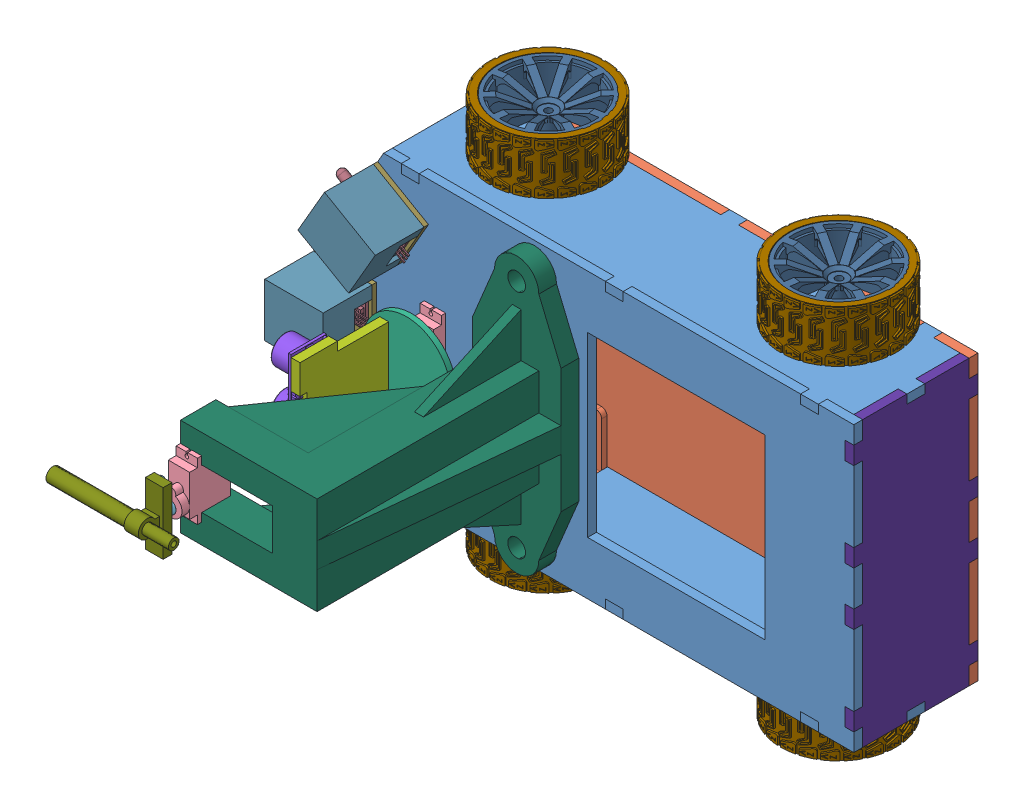
SolidWorks assembly Assemblage1, configuration Défaut. Lengths in mm.
Overall size (311.28 221.6 246.41).
49 component instances, 20 part files, 76 mates.
Components (placement in the parent):
- sides cage-1: sides cage [Défaut] at (1.2167 74.5307 344.188) x (1 0 0) z (0 -1 0) size (265 70 5)
- Support moteur-1: Support moteur [Défaut] at (-83.1833 74.5307 314.388) x (0 -1 0) z (-1 0 0) size (33 33 26)
- Support moteur-2: Support moteur [Défaut] at (80.6167 74.5307 314.388) x (0 -1 0) z (-1 0 0) size (33 33 26)
- GearMotor_25GA370-34 24V-TRUNSUN-1: GearMotor_25GA370-34 24V-TRUNSUN [Predeterminada] at (-83.1833 71.5307 334.388) x (0 -1 0) z (1 0 0) size (68.96 25 25)
- GearMotor_25GA370-34 24V-TRUNSUN-2: GearMotor_25GA370-34 24V-TRUNSUN [Predeterminada] at (80.6167 71.5307 334.388) x (0 -1 0) z (1 0 0) size (68.96 25 25)
- sides cage-4: sides cage [Défaut] at (1.2167 -80.4693 344.188) x (1 0 0) z (0 -1 0) size (265 70 5)
- Support moteur-3: Support moteur [Défaut] at (-83.1833 -85.4693 314.388) x (0 1 0) z (1 0 0) size (33 33 26)
- Support moteur-4: Support moteur [Défaut] at (80.6167 -85.4693 314.388) x (0 1 0) z (1 0 0) size (33 33 26)
- GearMotor_25GA370-34 24V-TRUNSUN-3: GearMotor_25GA370-34 24V-TRUNSUN [Predeterminada] at (-83.1833 -82.4693 334.388) x (0 1 0) z (-1 0 0) size (68.96 25 25)
- GearMotor_25GA370-34 24V-TRUNSUN-4: GearMotor_25GA370-34 24V-TRUNSUN [Predeterminada] at (80.6167 -82.4693 334.388) x (0 1 0) z (-1 0 0) size (68.96 25 25)
- rough_body-1: rough_body [Default] at (-102.2833 -2.1693 385.988) x (0 1 0) z (1 0 0) size (32.4 30.3 12)
- part 7 .1-1: part 7 .1 [Default] at (-102.2833 -7.6693 392.2972) x (1 0 0) z (0 1 0) size (7.3 5 34)
- base-1: base [Default] at (-102.2833 -7.6693 392.2972) x (0 1 0) z (0 0 1) size (50 50 3)
- vertical-1: vertical [Default] at (-117.2833 -7.6693 420.2972) x (0 1 0) z (1 0 0) size (45 53 5)
- compUltrasonic HCSR04-1: compUltrasonic HCSR04 [Default] at (-118.7833 41.4801 356.1344) x (0 1 0) z (-1 0 0) size (45 24.45 19.22)
- wheel-6: wheel [Default] at (90.8734 -44.1342 276.598) x (1 0 0) z (0 -1 0) size (65.01 65.01 29.8)
  - 65mm tire-1: 65mm tire [Default] at (-10.6774 57.7897 57.6351) size (65.01 65.01 29)
  - blue_wheel_frame-1: blue_wheel_frame [Default] at (-10.2563 57.7897 57.6351) x (0 0 -1) z (0.137869 0.990451 0) size (29 56 56)
  - motor_adapter-2: motor_adapter [Default] at (-10.2567 57.79 54.3351) x (0.788821 -0.614623 0) z (0 0 1) size (13.7 12 18.23)
- wheel-7: wheel [Default] at (-72.9266 -44.1342 276.598) x (1 0 0) z (0 -1 0) size (65.01 65.01 29.8)
  - 65mm tire-1: 65mm tire [Default] at (-10.6774 57.7897 57.6351) size (65.01 65.01 29)
  - blue_wheel_frame-1: blue_wheel_frame [Default] at (-10.2563 57.7897 57.6351) x (0 0 -1) z (0.137869 0.990451 0) size (29 56 56)
  - motor_adapter-2: motor_adapter [Default] at (-10.2567 57.79 54.3351) x (0.788821 -0.614623 0) z (0 0 1) size (13.7 12 18.23)
- wheel-8: wheel [Default] at (90.8734 33.1955 392.178) x (1 0 0) z (0 1 0) size (65.01 65.01 29.8)
  - 65mm tire-1: 65mm tire [Default] at (-10.6774 57.7897 57.6351) size (65.01 65.01 29)
  - blue_wheel_frame-1: blue_wheel_frame [Default] at (-10.2563 57.7897 57.6351) x (0 0 -1) z (0.137869 0.990451 0) size (29 56 56)
  - motor_adapter-2: motor_adapter [Default] at (-10.2567 57.79 54.3351) x (0.788821 -0.614623 0) z (0 0 1) size (13.7 12 18.23)
- wheel-9: wheel [Default] at (-72.9266 33.1955 392.178) x (1 0 0) z (0 1 0) size (65.01 65.01 29.8)
  - 65mm tire-1: 65mm tire [Default] at (-10.6774 57.7897 57.6351) size (65.01 65.01 29)
  - blue_wheel_frame-1: blue_wheel_frame [Default] at (-10.2563 57.7897 57.6351) x (0 0 -1) z (0.137869 0.990451 0) size (29 56 56)
  - motor_adapter-2: motor_adapter [Default] at (-10.2567 57.79 54.3351) x (0.788821 -0.614623 0) z (0 0 1) size (13.7 12 18.23)
- BASSE BC IR-1: BASSE BC IR [Défaut] at (-125.773 51.0749 379.188) x (0.866025 -0.5 0) z (0 0 1) size (33 30 2.5)
- Light sensor LM393-1: Light sensor LM393 [По умолчанию] at (-128.3725 48.0724 382.188) x (-0.866025 0.5 0) z (0.5 0.866025 0) size (46.18 7.1 14.2)
- cache bc IR-1: cache bc IR [Défaut] at (-129.773 44.1467 409.188) x (0.866025 -0.5 0) z (0 0 -1) size (33 30 30)
- BASSE BC IR-2: BASSE BC IR [Défaut] at (-129.773 -55.0854 379.188) x (0.866025 0.5 0) z (0 0 1) size (33 30 2.5)
- Light sensor LM393-2: Light sensor LM393 [По умолчанию] at (-128.4725 -58.8379 382.188) x (-0.866025 -0.5 0) z (-0.5 0.866025 0) size (46.18 7.1 14.2)
- cache bc IR-2: cache bc IR [Défaut] at (-125.773 -62.0136 409.188) x (0.866025 0.5 0) z (0 0 -1) size (33 30 30)
- BASSE BC IR-3: BASSE BC IR [Défaut] at (-151.7833 -1.4693 379.188) size (33 30 2.5)
- Light sensor LM393-3: Light sensor LM393 [По умолчанию] at (-152.5333 -5.3693 382.188) x (-1 0 0) z (0 1 0) size (46.18 7.1 14.2)
- cache bc IR-3: cache bc IR [Défaut] at (-151.7833 -9.4693 409.188) x (1 0 0) z (0 0 -1) size (33 30 30)
- support tuyau-1: support tuyau [Défaut] at (-46.2833 -5.4693 379.188) x (0 1 0) z (0 0 1) size (155 89.5 135)
- rough_body-2: rough_body [Default] at (-104.7833 -5.5693 520.988) x (0 1 0) z (1 0 0) size (32.4 30.3 12)
- part 7 .1-2: part 7 .1 [Default] at (-104.7833 -11.0693 531.288) x (1 0 0) z (0 1 0) size (7.3 5 34)
- pistoler-1: pistoler [Défaut] at (-103.4317 -11.2295 536.288) x (0 -1 0) z (0 0 -1) size (35 68 17)
- back cage-2: back cage [Défaut] at (133.7167 -5.4693 344.188) x (0 -1 0) z (-1 0 0) size (160 70 5)
- front cage-4: front cage [Défaut] at (-150.0463 32.0323 344.188) x (0.5 0.866025 0) z (-0.866025 0.5 0) size (92.38 70 5)
- front cage-5: front cage [Défaut] at (-150.0482 -42.9676 344.188) x (0.5 -0.866025 0) z (-0.866025 -0.5 0) size (92.38 70 5)
- roof-2: roof [Défaut] at (1.2167 -5.4693 374.188) size (311.19 160 5)
- baasssss final-1: baasssss final [Défaut] at (1.2167 -5.4693 309.188) size (311.19 160 5)
Mates (geometry in assembly coordinates):
- Parallèle9: parallel anti-aligned: plane of sides cage-1 through (1.2167 69.5307 344.188) normal (0 -1 0); plane of Support moteur-1 through (-70.1833 74.5307 318.388) normal (0 1 0)
- Coaxiale2: concentric anti-aligned: cylinder of sides cage-1 through (-83.1833 69.5307 334.388) axis (0 1 0) radius 13.1; cylinder of Support moteur-1 through (-83.1833 74.5307 334.388) axis (0 -1 0) radius 13
- Coïncidente18: coincident aligned: plane of sides cage-1 through (1.2167 74.5307 344.188) normal (0 1 0); plane of Support moteur-1 through (-70.1833 74.5307 318.388) normal (0 1 0)
- Coaxiale3: concentric anti-aligned: cylinder of sides cage-1 through (80.6167 69.5307 334.388) axis (0 1 0) radius 13.1; cylinder of Support moteur-2 through (80.6167 74.5307 334.388) axis (0 -1 0) radius 13
- Coïncidente19: coincident aligned: plane of sides cage-1 through (1.2167 74.5307 344.188) normal (0 1 0); plane of Support moteur-2 through (93.6167 74.5307 318.388) normal (0 1 0)
- Coaxiale4: concentric anti-aligned: cylinder of Support moteur-1 through (-74.6833 74.5307 334.388) axis (0 -1 0) radius 1.6; circle of GearMotor_25GA370-34 24V-TRUNSUN-1
- Coaxiale5: concentric anti-aligned: cylinder of Support moteur-1 through (-91.6833 74.5307 334.388) axis (0 -1 0) radius 1.6; circle of GearMotor_25GA370-34 24V-TRUNSUN-1
- Distance1: distance = 0 mm anti-aligned: plane of GearMotor_25GA370-34 24V-TRUNSUN-1 through (-83.1833 71.5307 330.888) normal (0 1 0); plane of Support moteur-1 through (-70.1833 71.5307 318.388) normal (0 -1 0)
- Coaxiale6: concentric anti-aligned: cylinder of Support moteur-2 through (89.1167 74.5307 334.388) axis (0 -1 0) radius 1.6; circle of GearMotor_25GA370-34 24V-TRUNSUN-2
- Coaxiale7: concentric anti-aligned: cylinder of Support moteur-2 through (72.1167 74.5307 334.388) axis (0 -1 0) radius 1.6; circle of GearMotor_25GA370-34 24V-TRUNSUN-2
- Coïncidente22: coincident anti-aligned: plane of Support moteur-2 through (93.6167 71.5307 318.388) normal (0 -1 0); plane of GearMotor_25GA370-34 24V-TRUNSUN-2 through (80.6167 71.5307 330.888) normal (0 1 0)
- Coaxiale8: concentric aligned: cylinder of sides cage-4 through (-83.1833 -85.4693 334.388) axis (0 1 0) radius 13.1; cylinder of Support moteur-3 through (-83.1833 -85.4693 334.388) axis (0 1 0) radius 13
- Coïncidente27: coincident aligned: plane of sides cage-4 through (1.2167 -85.4693 344.188) normal (0 -1 0); plane of Support moteur-3 through (-96.1833 -85.4693 318.388) normal (0 -1 0)
- Coaxiale9: concentric aligned: cylinder of sides cage-4 through (80.6167 -85.4693 334.388) axis (0 1 0) radius 13.1; cylinder of Support moteur-4 through (80.6167 -85.4693 334.388) axis (0 1 0) radius 13
- Coïncidente29: coincident aligned: plane of sides cage-4 through (1.2167 -85.4693 344.188) normal (0 -1 0); plane of Support moteur-4 through (67.6167 -85.4693 318.388) normal (0 -1 0)
- Coaxiale10: concentric aligned: cylinder of Support moteur-3 through (-91.6833 -85.4693 334.388) axis (0 1 0) radius 1.6; circle of GearMotor_25GA370-34 24V-TRUNSUN-3
- Coaxiale11: concentric anti-aligned: cylinder of Support moteur-3 through (-74.6833 -85.4693 334.388) axis (0 1 0) radius 1.6; circle of GearMotor_25GA370-34 24V-TRUNSUN-3
- Coïncidente30: coincident anti-aligned: plane of Support moteur-3 through (-96.1833 -82.4693 318.388) normal (0 1 0); plane of GearMotor_25GA370-34 24V-TRUNSUN-3 through (-83.1833 -82.4693 330.888) normal (0 -1 0)
- Coaxiale12: concentric anti-aligned: cylinder of Support moteur-4 through (72.1167 -85.4693 334.388) axis (0 1 0) radius 1.6; circle of GearMotor_25GA370-34 24V-TRUNSUN-4
- Coaxiale13: concentric anti-aligned: cylinder of Support moteur-4 through (89.1167 -85.4693 334.388) axis (0 1 0) radius 1.6; cylinder of GearMotor_25GA370-34 24V-TRUNSUN-4 through (89.1167 -72.4693 334.388) axis (0 -1 0) radius 1.5
- Coïncidente31: coincident anti-aligned: plane of Support moteur-4 through (67.6167 -82.4693 318.388) normal (0 1 0); plane of GearMotor_25GA370-34 24V-TRUNSUN-4 through (80.6167 -82.4693 330.888) normal (0 -1 0)
- Coaxiale14: concentric aligned: circle of rough_body-1; cylinder of part 7 .1-1 through (-102.2833 -7.6693 387.2972) axis (0 0 1) radius 3.6484
- Coïncidente45: coincident anti-aligned: plane of part 7 .1-1 through (-102.2833 -22.4193 392.2972) normal (0 0 1); plane of base-1 through (-102.2833 -7.6693 392.2972) normal (0 0 -1)
- Coaxiale16: concentric aligned: circle of part 7 .1-1; circle of base-1
- Parallèle15: parallel: line of rough_body-1 through (-108.2833 9.3307 385.988) axis (0 -1 0); plane of base-1 through (-112.2833 -20.1693 395.2972) normal (-1 0 0)
- Coïncidente46: coincident aligned: line of base-1 through (-117.2833 4.8307 392.2972) axis (0 1 0); line of vertical-1 through (-117.2833 4.8307 392.2972) axis (0 1 0)
- Coïncidente47: coincident anti-aligned: line of base-1 through (-117.2833 9.8307 392.2972) axis (1 0 0); line of vertical-1 through (-112.2833 9.8307 392.2972) axis (-1 0 0)
- Coïncidente48: coincident anti-aligned: plane of vertical-1 through (-117.2833 -7.6693 420.2972) normal (-1 0 0); plane of compUltrasonic HCSR04-1 through (-117.2833 41.4801 356.1344) normal (1 0 0)
- Coïncidente49: coincident aligned: plane of vertical-1 through (-112.2833 14.8307 395.2972) normal (0 1 0); plane of compUltrasonic HCSR04-1 through (-120.2833 14.8307 423.7972) normal (0 1 0)
- Coïncidente50: coincident anti-aligned: plane of vertical-1 through (-117.2833 -13.6693 441.2972) normal (0 0 1); plane of compUltrasonic HCSR04-1 through (-116.2833 -56.8187 441.2972) normal (0 0 -1)
- Distance11: distance = 1 mm anti-aligned: plane of wheel-6/motor_adapter-2 through (80.6167 -86.4693 334.388) normal (0 1 0); plane of Support moteur-4 through (67.6167 -85.4693 318.388) normal (0 -1 0)
- Coaxiale21: concentric aligned: cylinder of GearMotor_25GA370-34 24V-TRUNSUN-4 through (80.6167 -105.1529 334.388) axis (0 -1 0) radius 2; cylinder of wheel-6/motor_adapter-2 through (80.6167 -86.4693 334.388) axis (0 -1 0) radius 2.09
- Distance12: distance = 1 mm anti-aligned: plane of wheel-7/motor_adapter-2 through (-83.1833 -86.4693 334.388) normal (0 1 0); plane of Support moteur-3 through (-96.1833 -85.4693 318.388) normal (0 -1 0)
- Coaxiale22: concentric aligned: cylinder of GearMotor_25GA370-34 24V-TRUNSUN-3 through (-83.1833 -105.1529 334.388) axis (0 -1 0) radius 2; cylinder of wheel-7/motor_adapter-2 through (-83.1833 -86.4693 334.388) axis (0 -1 0) radius 2.09
- Distance13: distance = 1 mm anti-aligned: plane of Support moteur-2 through (93.6167 74.5307 318.388) normal (0 1 0); plane of wheel-8/motor_adapter-2 through (80.6167 75.5307 334.388) normal (0 -1 0)
- Coaxiale23: concentric aligned: cylinder of GearMotor_25GA370-34 24V-TRUNSUN-2 through (80.6167 94.2142 334.388) axis (0 1 0) radius 2; cylinder of wheel-8/motor_adapter-2 through (80.6167 75.5307 334.388) axis (0 1 0) radius 2.09
- Distance14: distance = 1 mm anti-aligned: plane of Support moteur-1 through (-70.1833 74.5307 318.388) normal (0 1 0); plane of wheel-9/motor_adapter-2 through (-83.1833 75.5307 334.388) normal (0 -1 0)
- Coaxiale24: concentric aligned: cylinder of GearMotor_25GA370-34 24V-TRUNSUN-1 through (-83.1833 94.2142 334.388) axis (0 1 0) radius 2; cylinder of wheel-9/motor_adapter-2 through (-83.1833 75.5307 334.388) axis (0 1 0) radius 2.09
- Coïncidente56: coincident anti-aligned: plane of BASSE BC IR-1 through (-125.773 51.0749 381.688) normal (0 0 1); plane of Light sensor LM393-1 through (-138.8643 55.4 381.688) normal (0 0 -1)
- Parallèle19: parallel aligned: plane of BASSE BC IR-1 through (-134.5624 68.8512 381.688) normal (0.5 0.866025 0); plane of Light sensor LM393-1 through (-138.4624 62.0962 383.788) normal (0.5 0.866025 0)
- Coïncidente57: coincident aligned: plane of BASSE BC IR-1 through (-149.5624 42.8704 381.688) normal (-0.866025 0.5 0); plane of Light sensor LM393-1 through (-138.4624 62.0962 383.788) normal (-0.866025 0.5 0)
- Distance16: distance = 7.8 mm aligned: plane of Light sensor LM393-1 through (-138.4624 62.0962 383.788) normal (0.5 0.866025 0); plane of BASSE BC IR-1 through (-134.5624 68.8512 381.688) normal (0.5 0.866025 0)
- Coaxiale25: concentric anti-aligned: cylinder of BASSE BC IR-1 through (-132.9153 62.7041 381.688) axis (0 0 -1) radius 1.25; cylinder of cache bc IR-1 through (-132.9153 62.7041 379.188) axis (0 0 1) radius 1.25
- Coaxiale26: concentric anti-aligned: cylinder of BASSE BC IR-1 through (-143.4153 44.5175 381.688) axis (0 0 -1) radius 1.25; cylinder of cache bc IR-1 through (-143.4153 44.5175 379.188) axis (0 0 1) radius 1.25
- Coïncidente58: coincident anti-aligned: plane of BASSE BC IR-1 through (-125.773 51.0749 381.688) normal (0 0 1); plane of cache bc IR-1 through (-129.773 44.1467 381.688) normal (0 0 -1)
- Coaxiale27: concentric anti-aligned: cylinder of BASSE BC IR-1 through (-132.9153 62.7041 381.688) axis (0 0 -1) radius 1.25; cylinder of cache bc IR-1 through (-132.9153 62.7041 379.188) axis (0 0 1) radius 1.25
- Coïncidente63: coincident anti-aligned: plane of BASSE BC IR-2 through (-129.773 -55.0854 381.688) normal (0 0 1); plane of Light sensor LM393-2 through (-140.0643 -64.2602 381.688) normal (0 0 -1)
- Coïncidente64: coincident aligned: plane of BASSE BC IR-2 through (-134.5624 -79.7898 381.688) normal (-0.866025 -0.5 0); plane of Light sensor LM393-2 through (-145.6624 -60.5641 383.788) normal (-0.866025 -0.5 0)
- Distance22: distance = 7.8 mm aligned: plane of Light sensor LM393-2 through (-145.6624 -60.5641 383.788) normal (-0.5 0.866025 0); plane of BASSE BC IR-2 through (-149.5624 -53.8091 381.688) normal (-0.5 0.866025 0)
- Coaxiale28: concentric anti-aligned: cylinder of BASSE BC IR-2 through (-143.4153 -55.4562 381.688) axis (0 0 -1) radius 1.25; cylinder of cache bc IR-2 through (-143.4153 -55.4562 379.188) axis (0 0 1) radius 1.25
- Coaxiale29: concentric anti-aligned: cylinder of BASSE BC IR-2 through (-132.9153 -73.6427 381.688) axis (0 0 -1) radius 1.25; cylinder of cache bc IR-2 through (-132.9153 -73.6427 379.188) axis (0 0 1) radius 1.25
- Coïncidente66: coincident anti-aligned: plane of BASSE BC IR-2 through (-129.773 -55.0854 381.688) normal (0 0 1); plane of cache bc IR-2 through (-125.773 -62.0136 381.688) normal (0 0 -1)
- Distance24: distance = 27 mm anti-aligned: plane of rough_body-1 through (-108.2833 -13.6693 362.988) normal (-1 0 0); plane of BASSE BC IR-3 through (-135.2833 -20.4693 381.688) normal (1 0 0)
- Coïncidente68: coincident anti-aligned: plane of BASSE BC IR-3 through (-151.7833 -1.4693 381.688) normal (0 0 1); plane of Light sensor LM393-3 through (-165.2833 -4.2693 381.688) normal (0 0 -1)
- Coïncidente69: coincident aligned: plane of BASSE BC IR-3 through (-168.2833 -20.4693 381.688) normal (-1 0 0); plane of Light sensor LM393-3 through (-168.2833 1.7307 383.788) normal (-1 0 0)
- Distance25: distance = 7.8 mm aligned: plane of Light sensor LM393-3 through (-168.2833 1.7307 383.788) normal (0 1 0); plane of BASSE BC IR-3 through (-168.2833 9.5307 381.688) normal (0 1 0)
- Coaxiale30: concentric anti-aligned: cylinder of BASSE BC IR-3 through (-163.7833 5.0307 381.688) axis (0 0 -1) radius 1.25; cylinder of cache bc IR-3 through (-163.7833 5.0307 379.188) axis (0 0 1) radius 1.25
- Coaxiale31: concentric anti-aligned: cylinder of BASSE BC IR-3 through (-163.7833 -15.9693 381.688) axis (0 0 -1) radius 1.25; cylinder of cache bc IR-3 through (-163.7833 -15.9693 379.188) axis (0 0 1) radius 1.25
- Coïncidente70: coincident anti-aligned: plane of BASSE BC IR-3 through (-151.7833 -1.4693 381.688) normal (0 0 1); plane of cache bc IR-3 through (-151.7833 -9.4693 381.688) normal (0 0 -1)
- Coïncidente76: coincident anti-aligned: plane of support tuyau-1 through (-81.5833 -17.0693 477.188) normal (0 1 0); plane of rough_body-2 through (-98.7833 -17.0693 497.988) normal (0 -1 0)
- Coïncidente77: coincident anti-aligned: plane of support tuyau-1 through (-46.2833 -5.4693 514.188) normal (0 0 1); plane of rough_body-2 through (-104.7833 -5.5693 514.188) normal (0 0 -1)
- Coïncidente78: coincident aligned: plane of support tuyau-1 through (-110.7833 -5.4693 379.188) normal (-1 0 0); plane of rough_body-2 through (-110.7833 -17.0693 497.988) normal (-1 0 0)
- Coaxiale32: concentric anti-aligned: cylinder of rough_body-2 through (-104.7833 -11.0693 525.288) axis (0 0 -1) radius 6; cylinder of part 7 .1-2 through (-104.7833 -11.0693 526.288) axis (0 0 1) radius 3.6484
- Distance29: distance = 1 mm anti-aligned: plane of part 7 .1-2 through (-104.7833 -11.0693 526.288) normal (0 0 -1); plane of rough_body-2 through (-104.7833 -5.5693 525.288) normal (0 0 1)
- Tangent1: tangent aligned: cylinder of part 7 .1-2 through (-88.4317 -11.0693 530.288) axis (0 0 1) radius 20; plane of pistoler-1 through (-108.4317 6.2705 531.288) normal (-1 0 0)
- Coïncidente80: coincident anti-aligned: plane of part 7 .1-2 through (-104.7833 -25.8193 531.288) normal (0 0 1); plane of pistoler-1 through (-103.4317 -11.2295 531.288) normal (0 0 -1)
- Distance31: distance = 32.4102 mm: plane of pistoler-1 through (-98.4317 -28.7295 531.288) normal (0 -1 0); cylinder of part 7 .1-2 through (-104.7833 3.6807 530.288) axis (0 0 1) radius 2.25
- Coïncidente83: coincident anti-aligned: plane of sides cage-4 through (128.7167 -85.4693 344.188) normal (1 0 0); plane of back cage-2 through (128.7167 -5.4693 344.188) normal (-1 0 0)
- Parallèle20: parallel anti-aligned: plane of sides cage-1 through (-131.2833 69.5307 344.188) normal (-1 0 0); plane of front cage-4 through (-131.2814 74.534 379.188) normal (1 0 0)
- Coïncidente90: coincident anti-aligned: plane of sides cage-4 through (-131.2833 -85.4693 344.188) normal (-1 0 0); plane of front cage-5 through (-131.2833 -85.4693 309.188) normal (1 0 0)
- Coïncidente97: coincident anti-aligned: plane of back cage-2 through (128.7167 -5.4693 374.188) normal (0 0 1); plane of roof-2 through (1.2167 -5.4693 374.188) normal (0 0 -1)
- Coïncidente98: coincident aligned: plane of back cage-2 through (133.7167 -5.4693 344.188) normal (1 0 0); plane of roof-2 through (133.7167 -5.4693 379.188) normal (1 0 0)
- Coïncidente99: coincident anti-aligned: plane of back cage-2 through (128.7167 54.5307 344.188) normal (0 -1 0); plane of roof-2 through (1.2167 54.5307 379.188) normal (0 1 0)
- Coïncidente100: coincident anti-aligned: plane of sides cage-1 through (1.2167 69.5307 314.188) normal (0 0 -1); plane of baasssss final-1 through (1.2167 -5.4693 314.188) normal (0 0 1)
- Coïncidente101: coincident aligned: plane of back cage-2 through (133.7167 -5.4693 344.188) normal (1 0 0); plane of baasssss final-1 through (133.7167 -5.4693 314.188) normal (1 0 0)
- Coïncidente103: coincident aligned: plane of sides cage-1 through (1.2167 74.5307 344.188) normal (0 1 0); plane of baasssss final-1 through (1.2167 74.5307 314.188) normal (0 1 0)
